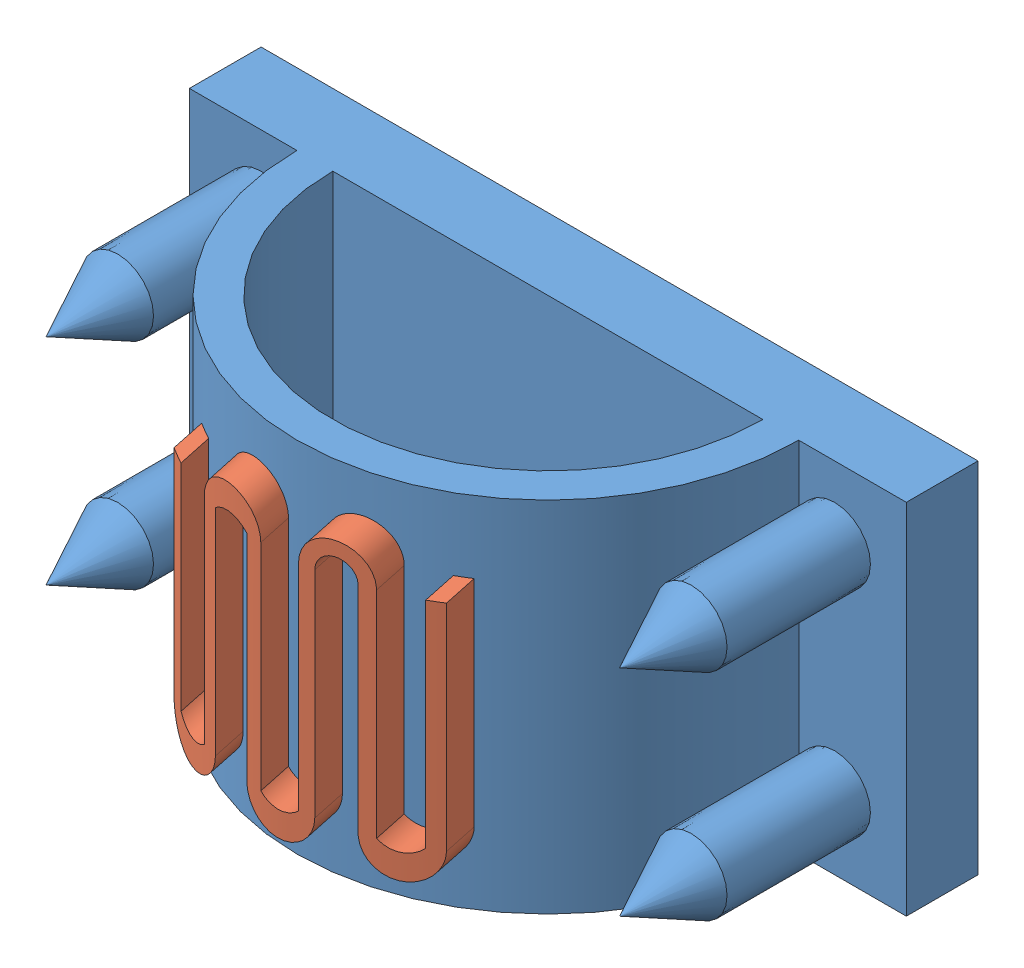
SolidWorks assembly assembly, configuration Default. Lengths in mm.
Overall size (100 50 54.37).
2 component instances, 2 part files, 2 mates.
Components (placement in the parent):
- substrate_front-1: substrate_front [Default] at (17.4412 96.0136 -48.9962) size (100 50 45)
- 3d print-3: 3d print [Default] at (17.4409 102.0907 -38.9958) x (0 1 0) z (-0.978288 0 0.207252) size (40.36 15.58 38.39)
Mates (geometry in assembly coordinates):
- Tangent2: tangent: cylinder of assembly; cylinder of substrate_front-1 through (17.4412 -7.2488 -38.9962) axis (0 1 0) radius 35; face of 3d print-3
- Distance1: distance = 10 mm aligned: plane of 3d print-3 through (1.0706 111.0136 -8.0601) normal (0 1 0); plane of substrate_front-1 through (67.4412 121.0136 -38.9962) normal (0 1 0)
